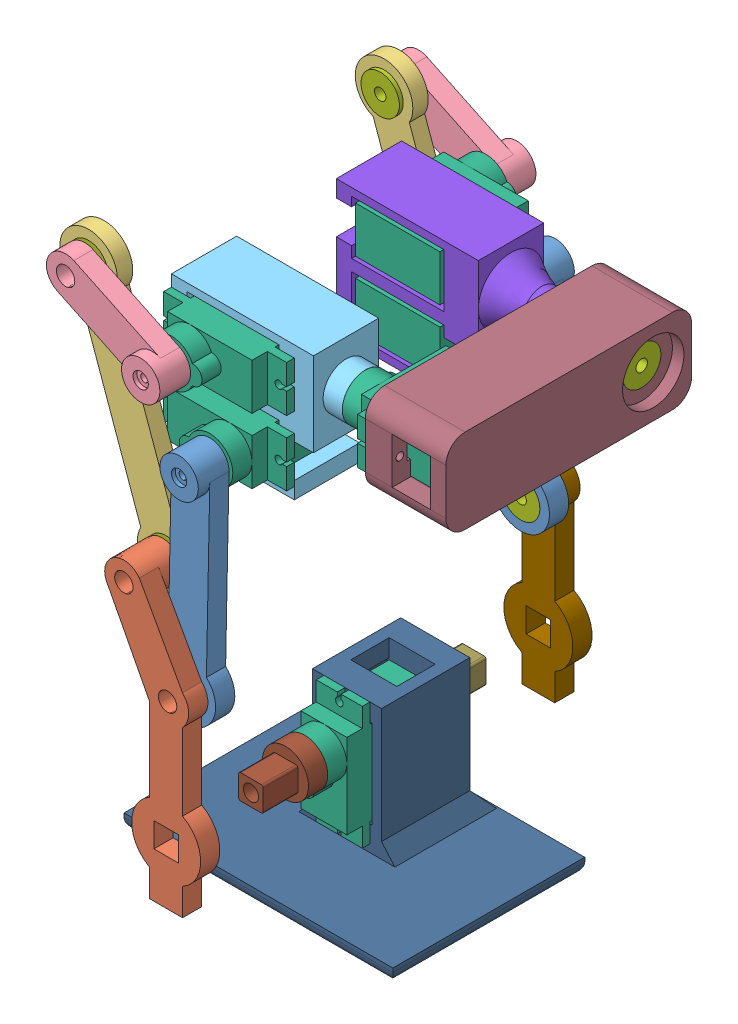
SolidWorks assembly prototype, configuration Default. Lengths in mm.
Overall size (98.32 150.19 101.95).
28 component instances, 13 part files, 2 mates.
Components (placement in the parent):
- Femur_right_back-1: Femur_right_back [Default] at (-0.8845 0.1087 -4) x (0.999045 -0.043687 0) z (0 0 1) size (15 62.49 8)
- Tibia_left-1: Tibia_left [Default] at (-0.8859 0.0097 1) x (0.498529 0.866873 0) z (0 0 1) size (60.64 52.18 10)
- Femur_right_front_upper-1: Femur_right_front_upper [Default] at (14.5674 -8.1519 -9) x (0.385848 -0.922563 0) z (0 0 1) size (74.92 18.18 4)
- Femur_left_upper-1: Femur_left_upper [Default] at (-82.8829 -0.1764 -4) x (0.452707 -0.891659 0) z (0 0 1) size (29.81 25.25 8)
- Femur_servo_case_left-1: Femur_servo_case_left [Default] at origin size (42 35 17)
- servo motor (mg90s) v1.step-1: servo motor (mg90s) v1.step [Default] at (0.1122 49.9799 -32) size (32 12 33)
- servo motor (mg90s) v1.step-2: servo motor (mg90s) v1.step [Default] at (0.1122 66.9799 -32) x (-1 0 0) z (0 0 1) size (32 12 33)
- bearing-5: bearing [Default] at (4.1242 -0.0103 0) x (0 0 -1) z (1 0 0) size (4 10 10)
- bearing-6: bearing [Default] at (-7.2746 21.2332 -5) x (0 0 -1) z (1 0 0) size (4 10 10)
- bearing-7: bearing [Default] at (-27.4548 77.7377 -5) x (0 0 -1) z (1 0 0) size (4 10 10)
- Femur_servo_case_right-1: Femur_servo_case_right [Default] at (0 0 -42.9503) size (67 35 20.15)
- servo motor (mg90s) v1.step-4: servo motor (mg90s) v1.step [Default] at (0.1122 66.9799 -57.9503) x (-1 0 0) z (0 0 -1) size (32 12 33)
- servo motor (mg90s) v1.step-5: servo motor (mg90s) v1.step [Default] at (0.1122 49.9799 -57.9503) x (1 0 0) z (0 0 -1) size (32 12 33)
- Femur_left_upper-2: Femur_left_upper [Default] at (-1.8268 169.8578 -85.9503) x (0.977755 0.209751 0) z (0 0 -1) size (29.81 25.25 8)
- Femur_right_front_upper-2: Femur_right_front_upper [Default] at (14.5674 -8.1519 -85.9503) x (0.385848 -0.922563 0) z (0 0 1) size (74.92 18.18 4)
- Femur_right_back-2: Femur_right_back [Default] at (9.1336 -0.0894 -85.9503) x (-0.999991 -0.004175 0) z (0 0 -1) size (15 62.49 8)
- Tibia_right-2: Tibia_right [Default] at (-0.8859 0.0097 -90.9503) x (0.498529 0.866873 0) z (0 0 1) size (60.64 52.18 10)
- bearing-2: bearing [Default] at (-7.2746 21.2332 -80.9503) x (0 0 -1) z (1 0 0) size (4 10 10)
- bearing-3: bearing [Default] at (4.1242 -0.0103 -89.9503) x (0 0 1) z (-1 0 0) size (4 10 10)
- bearing-4: bearing [Default] at (-27.4548 77.7377 -80.9503) x (0 0 -1) z (1 0 0) size (4 10 10)
- servo motor (mg90s) v1.step-6: servo motor (mg90s) v1.step [Default] at (3.7405 -36.8284 -58.0915) x (0 1 0) z (0 0 1) size (32 12 33)
- foot-1: foot [Default] at (-10.7433 61.7142 -16.7154) size (70 38 50)
- Servo_bracket-1: Servo_bracket [Default] at (0 0 -6.626) size (12 12 14)
- bearing-1: bearing [Default] at (3.7405 -31.8284 -64.0915) x (0 0 1) z (-1 0 0) size (4 10 10)
- foot_to_right_attachment-1: foot_to_right_attachment [Default] at (0 0 -6.626) size (6.5 6.5 10)
- servo motor (mg90s) v1.step-12: servo motor (mg90s) v1.step [Default] at (54.1122 65.0424 -28.5) x (0 0 1) z (-1 0 0) size (32 12 33)
- Hip_motor_case_right-1: Hip_motor_case_right [Default] at origin size (21 22 64)
- bearing-8: bearing [Default] at (55.1122 65.0424 -66.5) x (-1 0 0) z (0 0.034745 -0.999396) size (4 10 10)
Mates (geometry in assembly coordinates):
- Concentric1: concentric anti-aligned: cylinder of Hip_motor_case_right-1 through (72.2544 65.0424 -66.5) axis (-1 0 0) radius 5; cylinder of bearing-8 through (51.1122 65.0424 -66.5) axis (1 0 0) radius 5
- Coincident13: coincident aligned: plane of Hip_motor_case_right-1 through (55.1122 65.0424 -66.5) normal (1 0 0); plane of bearing-8 through (55.1122 65.0424 -66.5) normal (1 0 0)
